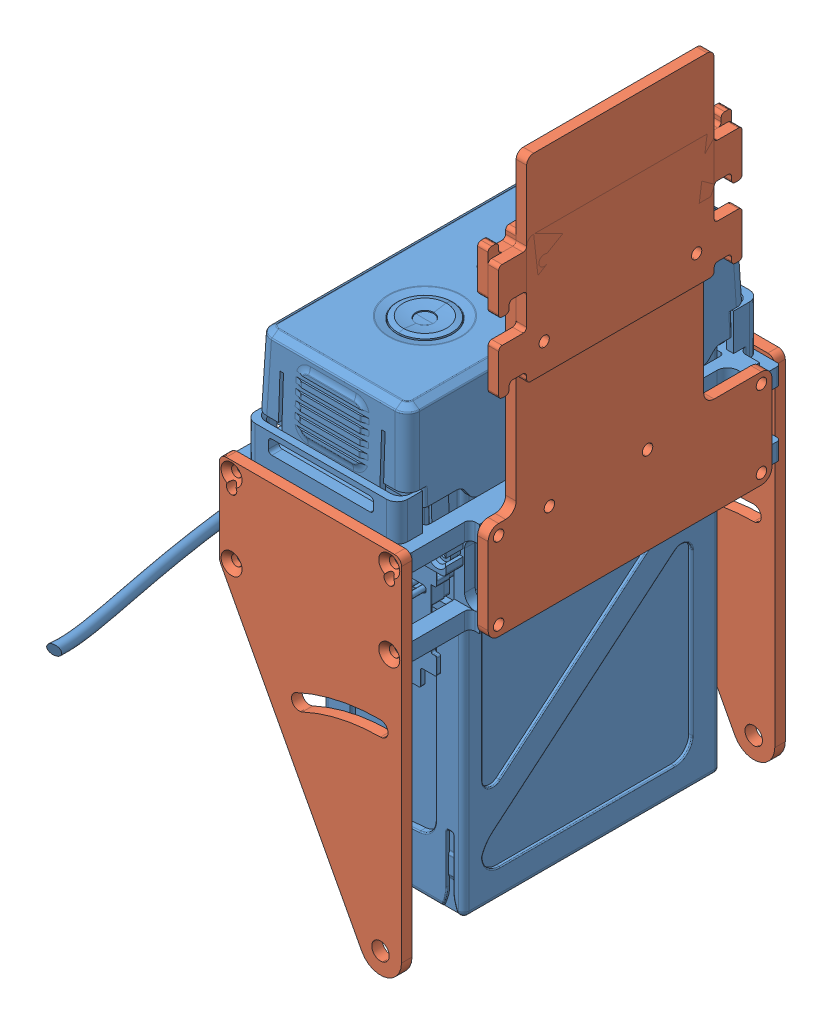
SolidWorks assembly 电池盒, configuration 默认. Lengths in mm.
Overall size (75.3 182 167.68).
2 component instances, 2 part files, 9 mates.
Components (placement in the parent):
- TB47D电池+电池架-1: TB47D电池+电池架 [默认] x (-1 0 0) z (0 0 -1) size (69.31 134.81 164.68)
- 电池架四周安装板-1: 电池架四周安装板 [默认] at (0.05 28 5.55) x (0 0 1) z (0 -1 0) size (109.5 59.7 182)
Mates (geometry in assembly coordinates):
- 重合1: coincident anti-aligned: plane of TB47D电池+电池架-1 through (0 0 0) normal (0 0 -1)
- 重合2: coincident aligned: plane of TB47D电池+电池架-1 through (0 0 0) normal (0 1 0)
- 重合3: coincident anti-aligned: plane of TB47D电池+电池架-1 through (0 0 0) normal (-1 0 0)
- 同心1: concentric aligned: cylinder of TB47D电池+电池架-1 through (22.55 21 -40.2) axis (0 0 -1) radius 1.25; cylinder of 电池架前板-1 through (22.55 21 -46.2) axis (0 0 -1) radius 1.5
- 同心2: concentric aligned: cylinder of TB47D电池+电池架-1 through (-22.45 21 -40.2) axis (0 0 -1) radius 1.25; cylinder of 电池架前板-1 through (-22.45 21 -46.2) axis (0 0 -1) radius 1.5
- 重合4: coincident anti-aligned: plane of TB47D电池+电池架-1 through (0.05 13.5 -46.2) normal (0 0 -1); plane of 电池架前板-1 through (20.05 -76.5055 -46.2) normal (0 0 1)
- 重合5: coincident anti-aligned: plane of TB47D电池+电池架-1 through (21.8 -20.483 57.3) normal (0 0 1); plane of 电池架四周安装板-1 through (20.05 -84.5 57.3) normal (0 0 -1)
- 同心3: concentric anti-aligned: cylinder of TB47D电池+电池架-1 through (-22.45 24.5 47.3) axis (0 0 1) radius 1.25; cylinder of 电池架四周安装板-1 through (-22.45 24.5 60.3) axis (0 0 -1) radius 1.5
- 同心4: concentric anti-aligned: cylinder of TB47D电池+电池架-1 through (22.55 24.5 47.3) axis (0 0 1) radius 1.25; cylinder of 电池架四周安装板-1 through (22.55 24.5 60.3) axis (0 0 -1) radius 1.5
